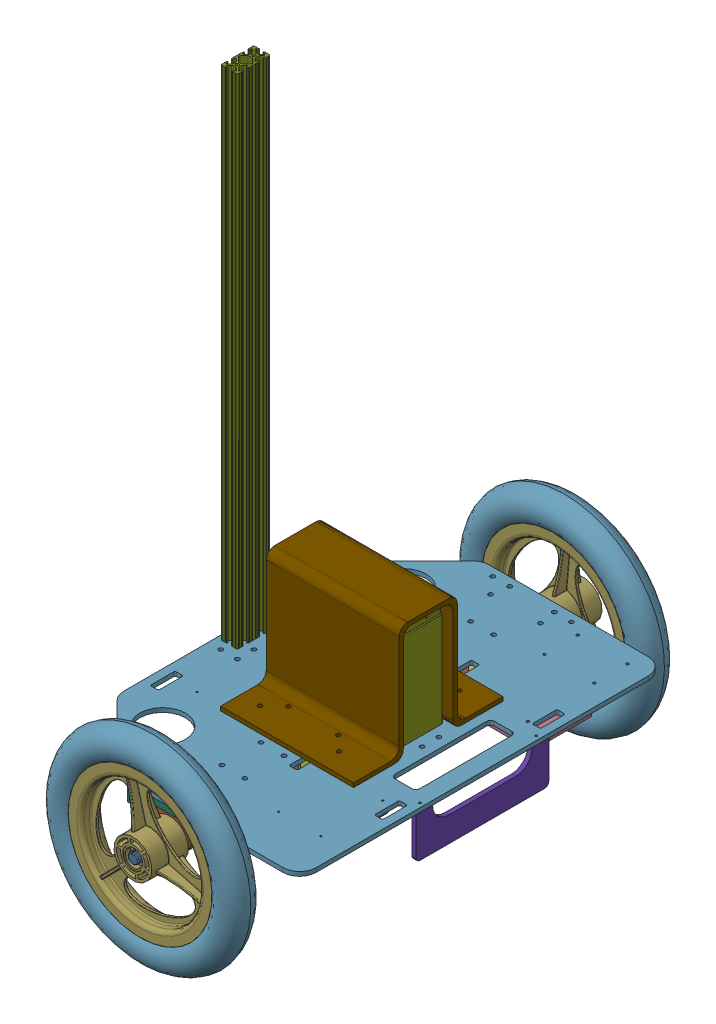
SolidWorks assembly Segway, configuration Default. Lengths in mm.
Overall size (381 985.87 688.87).
122 component instances, 36 part files, 61 mates.
Components (placement in the parent):
- BB2-1: BB2 [Default] at (0.4359 -31.75 -121.9313) x (0 -1 0) z (0 0 1) size (64.41 64.41 215.73)
  - BB2-InterfacePlate-1-1: BB2-InterfacePlate-1 [Default] at origin size (63.5 63.5 3.7)
  - BB2-BackPlate-1-1: BB2-BackPlate-1 [Default] at (0 0 -8.55) x (0 -1 0) z (0 0 1) size (63.5 63.5 22.41)
  - BB2-RingGear-1-1: BB2-RingGear-1 [Default] at (0 0 -15.25) x (1 0 0) z (0 0 -1) size (60 60 46.8)
  - BB2-FrontPlate-1-1: BB2-FrontPlate-1 [Default] at (0 0 -68.4) x (0 1 0) z (0 0 -1) size (63.5 63.5 18.7)
  - br-8-1-1: br-8-1 [Default] at (0 0 -70.7812) x (1 0 0) z (0 0 -1) size (28.57 28.57 7.94)
  - br-8-1-2: br-8-1 [Default] at (0 0 -62.8438) x (0.905117 -0.425162 0) z (0 0 1) size (28.57 28.57 7.94)
  - BB2-OutputShaft-1-1: BB2-OutputShaft-1 [Default] at (0 0 -112.85) x (0.213787 -0.97688 0) z (0 0 1) size (12.7 12.7 59)
  - CIM Motor-1-1: CIM Motor-1 [Default] at (0 0 8.85) x (1 0 0) z (0 0 -1) size (64.41 64.41 149.34)
    - CIM motor-1-1: CIM motor-1 [Default] at origin size (64.41 64.41 149.34)
    - 10-24 UNC x 4_ Phillips Pan Head-1-1: 10-24 UNC x 4_ Phillips Pan Head-1 [Default] at (0 25.4 -98.0336) x (1 0 0) z (0 1 0) size (9.47 105.24 9.47)
    - 10-24 UNC x 4_ Phillips Pan Head-1-2: 10-24 UNC x 4_ Phillips Pan Head-1 [Default] at (0 -25.4 -98.0336) x (-1 0 0) z (0 -1 0) size (9.47 105.24 9.47)
- BB2-2: BB2 [Default] at (0.4359 -31.75 121.9095) x (0 -1 0) z (0 0 -1) size (64.41 64.41 215.73)
  - BB2-InterfacePlate-1-1: BB2-InterfacePlate-1 [Default] at origin size (63.5 63.5 3.7)
  - BB2-BackPlate-1-1: BB2-BackPlate-1 [Default] at (0 0 -8.55) x (0 -1 0) z (0 0 1) size (63.5 63.5 22.41)
  - BB2-RingGear-1-1: BB2-RingGear-1 [Default] at (0 0 -15.25) x (1 0 0) z (0 0 -1) size (60 60 46.8)
  - BB2-FrontPlate-1-1: BB2-FrontPlate-1 [Default] at (0 0 -68.4) x (0 1 0) z (0 0 -1) size (63.5 63.5 18.7)
  - br-8-1-1: br-8-1 [Default] at (0 0 -70.7812) x (1 0 0) z (0 0 -1) size (28.57 28.57 7.94)
  - br-8-1-2: br-8-1 [Default] at (0 0 -62.8438) x (0.905117 -0.425162 0) z (0 0 1) size (28.57 28.57 7.94)
  - BB2-OutputShaft-1-1: BB2-OutputShaft-1 [Default] at (0 0 -112.85) x (0.213787 -0.97688 0) z (0 0 1) size (12.7 12.7 59)
  - CIM Motor-1-1: CIM Motor-1 [Default] at (0 0 8.85) x (1 0 0) z (0 0 -1) size (64.41 64.41 149.34)
    - CIM motor-1-1: CIM motor-1 [Default] at origin size (64.41 64.41 149.34)
    - 10-24 UNC x 4_ Phillips Pan Head-1-1: 10-24 UNC x 4_ Phillips Pan Head-1 [Default] at (0 25.4 -98.0336) x (1 0 0) z (0 1 0) size (9.47 105.24 9.47)
    - 10-24 UNC x 4_ Phillips Pan Head-1-2: 10-24 UNC x 4_ Phillips Pan Head-1 [Default] at (0 -25.4 -98.0336) x (-1 0 0) z (0 -1 0) size (9.47 105.24 9.47)
- coupling-1: coupling [Default] at (0.4359 -31.75 -250.6563) x (0 0 1) z (-0.996462 -0.084047 0) size (50.8 33.34 33.34)
- coupling-2: coupling [Default] at (0.4359 -31.75 250.6345) x (0 0 -1) z (-0.914394 0.404825 0) size (50.8 33.34 33.34)
- 5_8_keyed_shaft-1: 5_8_keyed_shaft [Default] at (0.4359 -31.75 -230.0594) x (0 0 -1) z (-0.98071 -0.195469 0) size (114.47 15.59 15.88)
- 5_8_keyed_shaft-2: 5_8_keyed_shaft [Default] at (0.4359 -31.75 344.3376) x (0 0 -1) z (0.997156 -0.07537 0) size (114.47 15.59 15.88)
- bearing-1: bearing [Default] at (0.4359 -31.75 -279.2313) x (0 0 1) z (1 0 0) size (34.53 44.45 85.72)
- bearing-4: bearing [Default] at (0.4359 -31.75 279.2095) x (0 0 -1) z (-1 0 0) size (34.53 44.45 85.72)
- 12 Inch Wheel-1: 12 Inch Wheel [Default] at (0.4359 -31.75 -316.3594) x (0 0 -1) z (0.995996 -0.0894 0) size (56 304.8 304.8)
  - 12 Inch Wheel Outer Hub-1: 12 Inch Wheel Outer Hub [Default] at origin size (56 220 220)
  - 12 Inch Wheel Inner Hub-1: 12 Inch Wheel Inner Hub [Default] at (18.355 0 0) x (0 0 1) z (-1 0 0) size (27 27 46.36)
  - 12 Inch Tire-1: 12 Inch Tire [Default] at origin size (46.35 304.8 304.8)
- 12 Inch Wheel-2: 12 Inch Wheel [Default] at (0.4359 -31.75 316.3376) x (0 0 1) z (0.250945 0.968001 0) size (56 304.8 304.8)
  - 12 Inch Wheel Outer Hub-1: 12 Inch Wheel Outer Hub [Default] at origin size (56 220 220)
  - 12 Inch Wheel Inner Hub-1: 12 Inch Wheel Inner Hub [Default] at (18.355 0 0) x (0 0 1) z (-1 0 0) size (27 27 46.36)
  - 12 Inch Tire-1: 12 Inch Tire [Default] at origin size (46.35 304.8 304.8)
- bearing spacer-1: bearing spacer [Default] at (-42.4266 -9.525 -253.8313) size (85.72 9.53 25.4)
- bearing spacer-2: bearing spacer [Default] at (-42.4266 -9.525 279.2095) size (85.72 9.53 25.4)
- battery-1: battery [Default] at (-48.3252 6.35 -21.138) x (1 0 0) z (0 1 0) size (177.81 76.21 167.14)
- Maxi Fuse Block-1: Maxi Fuse Block [Default] at (120.15 0 161.55) x (0 0 -1) z (0 -1 0) size (107.5 77.5 38)
  - Maxi Fuse Block - Base-1: Maxi Fuse Block - Base [Default] at origin size (107.5 77.5 19.5)
  - Maxi Fuse Block - Terminal-1: Maxi Fuse Block - Terminal [Default] at (26.42 -26.73 16.2) x (1 0 0) z (0 -1 0) size (28 19.9 11.5)
  - Maxi Fuse Block - Terminal-2: Maxi Fuse Block - Terminal [Default] at (-26.42 -26.73 16.2) x (-1 0 0) z (0 1 0) size (28 19.9 11.5)
  - Maxi Fuse Block - Terminal-3: Maxi Fuse Block - Terminal [Default] at (26.42 -8.91 16.2) x (1 0 0) z (0 -1 0) size (28 19.9 11.5)
  - Maxi Fuse Block - Terminal-4: Maxi Fuse Block - Terminal [Default] at (-26.42 -8.91 16.2) x (-1 0 0) z (0 1 0) size (28 19.9 11.5)
  - Maxi Fuse Block - Terminal-5: Maxi Fuse Block - Terminal [Default] at (26.42 8.91 16.2) x (1 0 0) z (0 -1 0) size (28 19.9 11.5)
  - Maxi Fuse Block - Terminal-6: Maxi Fuse Block - Terminal [Default] at (-26.42 8.91 16.2) x (-1 0 0) z (0 1 0) size (28 19.9 11.5)
  - Maxi Fuse Block - Terminal-7: Maxi Fuse Block - Terminal [Default] at (26.42 26.73 16.2) x (1 0 0) z (0 -1 0) size (28 19.9 11.5)
  - Maxi Fuse Block - Terminal-8: Maxi Fuse Block - Terminal [Default] at (-26.42 26.73 16.2) x (-1 0 0) z (0 1 0) size (28 19.9 11.5)
  - Maxi Fuse Block - Bottom Cover-1: Maxi Fuse Block - Bottom Cover [Default] at (4.987 4.269 1.62) x (-1 0 0) z (0 0 -1) size (84 68 1.62)
  - Maxi Fuse Block - Top Cover-1: Maxi Fuse Block - Top Cover [Default] at (0 0 5.6) size (81 73.4 21.5)
  - Maxi Fuse-1: Maxi Fuse [Default] at (0.245 -26.664 28.75) size (29.25 8.9 31.25)
    - Maxi Fuse - Body-1: Maxi Fuse - Body [Default] at origin size (29.25 8.9 18.5)
    - Maxi Fuse - Terminal-1: Maxi Fuse - Terminal [Default] at (10.625 0 -12.75) x (-1 0 0) z (0 1 0) size (8 18.5 0.86)
    - Maxi Fuse - Terminal-2: Maxi Fuse - Terminal [Default] at (-10.625 0 -12.75) x (1 0 0) z (0 -1 0) size (8 18.5 0.86)
  - Maxi Fuse-2: Maxi Fuse [Default] at (0.245 -8.664 28.75) size (29.25 8.9 31.25)
    - Maxi Fuse - Body-1: Maxi Fuse - Body [Default] at origin size (29.25 8.9 18.5)
    - Maxi Fuse - Terminal-1: Maxi Fuse - Terminal [Default] at (10.625 0 -12.75) x (-1 0 0) z (0 1 0) size (8 18.5 0.86)
    - Maxi Fuse - Terminal-2: Maxi Fuse - Terminal [Default] at (-10.625 0 -12.75) x (1 0 0) z (0 -1 0) size (8 18.5 0.86)
  - Maxi Fuse-3: Maxi Fuse [Default] at (0.245 9.336 28.75) size (29.25 8.9 31.25)
    - Maxi Fuse - Body-1: Maxi Fuse - Body [Default] at origin size (29.25 8.9 18.5)
    - Maxi Fuse - Terminal-1: Maxi Fuse - Terminal [Default] at (10.625 0 -12.75) x (-1 0 0) z (0 1 0) size (8 18.5 0.86)
    - Maxi Fuse - Terminal-2: Maxi Fuse - Terminal [Default] at (-10.625 0 -12.75) x (1 0 0) z (0 -1 0) size (8 18.5 0.86)
  - Maxi Fuse-4: Maxi Fuse [Default] at (0.245 27.336 28.75) size (29.25 8.9 31.25)
    - Maxi Fuse - Body-1: Maxi Fuse - Body [Default] at origin size (29.25 8.9 18.5)
    - Maxi Fuse - Terminal-1: Maxi Fuse - Terminal [Default] at (10.625 0 -12.75) x (-1 0 0) z (0 1 0) size (8 18.5 0.86)
    - Maxi Fuse - Terminal-2: Maxi Fuse - Terminal [Default] at (-10.625 0 -12.75) x (1 0 0) z (0 -1 0) size (8 18.5 0.86)
- Victor884-1: Victor884 [Default] at (-101.5293 0.127 63.0431) x (0 0 -1) z (0 -1 0) size (69.65 56.95 53.28)
  - Victor884-Cover-1: Victor884-Cover [Default] at origin size (69.65 56.95 53.28)
  - Fan-PAPST-412-1: Fan-PAPST-412 [Default] at (-18.7322 -1.3534 40.2082) x (1 0 0) z (0 0 -1) size (39.88 39.88 20.07)
  - Victor884-Base-1: Victor884-Base [Default] at (6.7866 -24.0693 0.127) size (66.29 53.59 9.91)
  - Victor884-Capacitor-1: Victor884-Capacitor [Default] at (-18.6052 -1.2264 18.3642) x (0.989031 0.147708 0) z (0 0 1) size (12.7 12.7 20.33)
  - Victor884-LED - Green-1: Victor884-LED - Green [Default] at (7.0869 -27.9091 8.7012) x (0.893703 -0.448659 0) z (-0.448659 -0.893703 0) size (5.9 9 5.9)
  - Victor884-Fet-1: Victor884-Fet [Default] at (-12.6489 -15.1964 10.8712) x (0 1 0) z (1 0 0) size (10.16 22.61 4.47)
  - Victor884-Fet-2: Victor884-Fet [Default] at (-20.0149 -15.1964 10.8712) x (0 1 0) z (1 0 0) size (10.16 22.61 4.47)
  - Victor884-Fet-3: Victor884-Fet [Default] at (-27.3809 -15.1964 10.8712) x (0 1 0) z (1 0 0) size (10.16 22.61 4.47)
  - Victor884-Fet-4: Victor884-Fet [Default] at (-4.6352 4.7299 10.8712) x (-1 0 0) z (0 1 0) size (10.16 22.61 4.47)
  - Victor884-Fet-5: Victor884-Fet [Default] at (-4.6352 -2.6361 10.8712) x (-1 0 0) z (0 1 0) size (10.16 22.61 4.47)
  - Victor884-Fet-6: Victor884-Fet [Default] at (-4.6352 -10.0021 10.8712) x (-1 0 0) z (0 1 0) size (10.16 22.61 4.47)
  - Victor884-Fet-7: Victor884-Fet [Default] at (-24.5615 12.7436 10.8712) x (0 -1 0) z (-1 0 0) size (10.16 22.61 4.47)
  - Victor884-Fet-8: Victor884-Fet [Default] at (-17.1955 12.7436 10.8712) x (0 -1 0) z (-1 0 0) size (10.16 22.61 4.47)
  - Victor884-Fet-9: Victor884-Fet [Default] at (-9.8295 12.7436 10.8712) x (0 -1 0) z (-1 0 0) size (10.16 22.61 4.47)
  - Victor884-Fet-10: Victor884-Fet [Default] at (-32.5752 -7.1827 10.8712) x (1 0 0) z (0 -1 0) size (10.16 22.61 4.47)
  - Victor884-Fet-11: Victor884-Fet [Default] at (-32.5752 0.1833 10.8712) x (1 0 0) z (0 -1 0) size (10.16 22.61 4.47)
  - Victor884-Fet-12: Victor884-Fet [Default] at (-32.5752 7.5493 10.8712) x (1 0 0) z (0 -1 0) size (10.16 22.61 4.47)
  - Victor884 Screw Terminal-1: Victor884 Screw Terminal [Default] at (-48.5772 12.6166 13.9192) x (1 0 0) z (0 0 -1) size (7.87 7.87 10.34)
  - Victor884 Screw Terminal-2: Victor884 Screw Terminal [Default] at (-48.5772 2.4566 13.9192) x (1 0 0) z (0 0 -1) size (7.87 7.87 10.34)
  - Victor884 Screw Terminal-3: Victor884 Screw Terminal [Default] at (3.6198 12.6166 13.9192) x (1 0 0) z (0 0 -1) size (7.87 7.87 10.34)
  - Victor884 Screw Terminal-4: Victor884 Screw Terminal [Default] at (3.6198 2.4566 13.9192) x (1 0 0) z (0 0 -1) size (7.87 7.87 10.34)
  - Victor884-3 Pin Connector-1: Victor884-3 Pin Connector [Default] at (-48.3232 -24.0229 8.3312) x (0 -1 0) z (0 0 1) size (2.54 7.62 11.43)
- Victor884-2: Victor884 [Default] at (-116.1487 0.127 -63.0431) x (0 0 1) z (0 -1 0) size (69.65 56.95 53.28)
  - Victor884-Cover-1: Victor884-Cover [Default] at origin size (69.65 56.95 53.28)
  - Fan-PAPST-412-1: Fan-PAPST-412 [Default] at (-18.7322 -1.3534 40.2082) x (1 0 0) z (0 0 -1) size (39.88 39.88 20.07)
  - Victor884-Base-1: Victor884-Base [Default] at (6.7866 -24.0693 0.127) size (66.29 53.59 9.91)
  - Victor884-Capacitor-1: Victor884-Capacitor [Default] at (-18.6052 -1.2264 18.3642) x (0.989031 0.147708 0) z (0 0 1) size (12.7 12.7 20.33)
  - Victor884-LED - Green-1: Victor884-LED - Green [Default] at (7.0869 -27.9091 8.7012) x (0.893703 -0.448659 0) z (-0.448659 -0.893703 0) size (5.9 9 5.9)
  - Victor884-Fet-1: Victor884-Fet [Default] at (-12.6489 -15.1964 10.8712) x (0 1 0) z (1 0 0) size (10.16 22.61 4.47)
  - Victor884-Fet-2: Victor884-Fet [Default] at (-20.0149 -15.1964 10.8712) x (0 1 0) z (1 0 0) size (10.16 22.61 4.47)
  - Victor884-Fet-3: Victor884-Fet [Default] at (-27.3809 -15.1964 10.8712) x (0 1 0) z (1 0 0) size (10.16 22.61 4.47)
  - Victor884-Fet-4: Victor884-Fet [Default] at (-4.6352 4.7299 10.8712) x (-1 0 0) z (0 1 0) size (10.16 22.61 4.47)
  - Victor884-Fet-5: Victor884-Fet [Default] at (-4.6352 -2.6361 10.8712) x (-1 0 0) z (0 1 0) size (10.16 22.61 4.47)
  - Victor884-Fet-6: Victor884-Fet [Default] at (-4.6352 -10.0021 10.8712) x (-1 0 0) z (0 1 0) size (10.16 22.61 4.47)
  - Victor884-Fet-7: Victor884-Fet [Default] at (-24.5615 12.7436 10.8712) x (0 -1 0) z (-1 0 0) size (10.16 22.61 4.47)
  - Victor884-Fet-8: Victor884-Fet [Default] at (-17.1955 12.7436 10.8712) x (0 -1 0) z (-1 0 0) size (10.16 22.61 4.47)
  - Victor884-Fet-9: Victor884-Fet [Default] at (-9.8295 12.7436 10.8712) x (0 -1 0) z (-1 0 0) size (10.16 22.61 4.47)
  - Victor884-Fet-10: Victor884-Fet [Default] at (-32.5752 -7.1827 10.8712) x (1 0 0) z (0 -1 0) size (10.16 22.61 4.47)
  - Victor884-Fet-11: Victor884-Fet [Default] at (-32.5752 0.1833 10.8712) x (1 0 0) z (0 -1 0) size (10.16 22.61 4.47)
  - Victor884-Fet-12: Victor884-Fet [Default] at (-32.5752 7.5493 10.8712) x (1 0 0) z (0 -1 0) size (10.16 22.61 4.47)
  - Victor884 Screw Terminal-1: Victor884 Screw Terminal [Default] at (-48.5772 12.6166 13.9192) x (1 0 0) z (0 0 -1) size (7.87 7.87 10.34)
  - Victor884 Screw Terminal-2: Victor884 Screw Terminal [Default] at (-48.5772 2.4566 13.9192) x (1 0 0) z (0 0 -1) size (7.87 7.87 10.34)
  - Victor884 Screw Terminal-3: Victor884 Screw Terminal [Default] at (3.6198 12.6166 13.9192) x (1 0 0) z (0 0 -1) size (7.87 7.87 10.34)
  - Victor884 Screw Terminal-4: Victor884 Screw Terminal [Default] at (3.6198 2.4566 13.9192) x (1 0 0) z (0 0 -1) size (7.87 7.87 10.34)
  - Victor884-3 Pin Connector-1: Victor884-3 Pin Connector [Default] at (-48.3232 -24.0229 8.3312) x (0 -1 0) z (0 0 1) size (2.54 7.62 11.43)
- controller-1: controller [Default] at (76.2 -7.9502 -260.35) x (0 0 1) z (-1 0 0) size (165.1 28.6 88.9)
- base-1: base [Default] x (0 0 -1) z (1 0 0) size (558.8 6.35 381)
- beam-1: beam [Default] at (-47.1891 0 -279.4) x (0 0 1) z (1 0 0) size (558.8 25.4 25.4)
- beam-2: beam [Default] at (73.4609 0 -279.4) x (0 0 1) z (1 0 0) size (558.8 25.4 25.4)
- 8020-1020-36in-1: 8020-1020-36in [Default] at (-87.6335 6.35 -41.3302) x (0 0 1) z (0 -1 0) size (50.8 25.4 762)
- plate-1: plate [Default] at (190.5 0 -0.117) x (0 0 1) z (-1 0 0) size (203.2 63.5 6.35)
- batteryholder-1: batteryholder [Default] at (113.0313 6.35 -109.1178) x (0 0 1) z (-1 0 0) size (228.6 177.8 203.2)
Mates (geometry in assembly coordinates):
- Concentric1: concentric anti-aligned: cylinder of BB2-1/BB2-OutputShaft-1-1; cylinder of BB2-2/BB2-OutputShaft-1-1
- Coincident1: coincident aligned: plane of BB2-1/BB2-BackPlate-1-1 through (35.3609 0 -123.1113) normal (0 1 0); plane of BB2-2/BB2-BackPlate-1-1 through (-34.4891 0 123.0895) normal (0 1 0)
- Distance1: distance = 12.7 mm anti-aligned: plane of BB2-1/CIM Motor-1-1/CIM motor-1-1 through (16.1801 -47.4942 -6.3609) normal (0 0 1); plane of BB2-2/CIM Motor-1-1/CIM motor-1-1 through (-15.3083 -47.4942 6.3391) normal (0 0 -1)
- Concentric2: concentric aligned: cylinder of BB2-1/BB2-OutputShaft-1-1; cylinder of coupling-1
- Concentric3: concentric aligned: cylinder of BB2-2/BB2-OutputShaft-1-1; cylinder of coupling-2
- Distance2: distance = 3.175 mm anti-aligned: plane of BB2-2/BB2-FrontPlate-1-1 through (35.3609 3.175 196.6595) normal (0 0 1); plane of coupling-2 through (0.4359 -31.75 199.8345) normal (0 0 -1)
- Distance3: distance = 3.175 mm anti-aligned: plane of BB2-1/BB2-FrontPlate-1-1 through (-34.4891 3.175 -196.6813) normal (0 0 -1); plane of coupling-1 through (0.4359 -31.75 -199.8563) normal (0 0 1)
- Concentric4: concentric anti-aligned: cylinder of coupling-1; cylinder of 5_8_keyed_shaft-1
- Concentric5: concentric aligned: cylinder of coupling-2; cylinder of 5_8_keyed_shaft-2
- Concentric6: concentric aligned: cylinder of 5_8_keyed_shaft-1; cylinder of bearing-1
- Parallel1: parallel aligned: plane of BB2-1/BB2-FrontPlate-1-1 through (-34.4891 0 -197.3163) normal (0 1 0); plane of bearing-1 through (-80.0705 -9.525 -253.8313) normal (0 1 0)
- Concentric8: concentric anti-aligned: cylinder of 5_8_keyed_shaft-2; cylinder of bearing-4
- Parallel2: parallel aligned: plane of BB2-2/BB2-FrontPlate-1-1 through (35.3609 0 197.2945) normal (0 1 0); plane of bearing-4 through (80.9423 -9.525 253.8095) normal (0 1 0)
- Distance7: distance = 3.175 mm anti-aligned: plane of coupling-1 through (0.4359 -31.75 -250.6563) normal (0 0 -1); plane of bearing-1 through (-80.0705 -16.0521 -253.8313) normal (0 0 1)
- Distance8: distance = 3.175 mm anti-aligned: plane of coupling-2 through (0.4359 -31.75 250.6345) normal (0 0 1); plane of bearing-4 through (80.9423 -16.0521 253.8095) normal (0 0 -1)
- Concentric13: concentric aligned: cylinder of 5_8_keyed_shaft-1; cylinder of 12 Inch Wheel-1/12 Inch Wheel Inner Hub-1
- Concentric14: concentric anti-aligned: cylinder of 5_8_keyed_shaft-2; cylinder of 12 Inch Wheel-2/12 Inch Wheel Inner Hub-1
- Coincident22: coincident anti-aligned: plane of bearing-4 through (0.4359 -31.75 288.3376) normal (0 0 1); plane of 12 Inch Wheel-2/12 Inch Wheel Inner Hub-1 through (-17.6655 -42.3983 288.3376) normal (0 0 -1)
- Coincident23: coincident anti-aligned: plane of bearing-1 through (0.4359 -31.75 -288.3594) normal (0 0 -1); plane of 12 Inch Wheel-1/12 Inch Wheel Inner Hub-1 through (-15.6822 -45.213 -288.3594) normal (0 0 1)
- Coincident14: coincident anti-aligned: plane of bearing-4 through (80.9423 -9.525 253.8095) normal (0 1 0); plane of bearing spacer-2 through (-42.4266 -9.525 253.8095) normal (0 -1 0)
- Concentric15: concentric anti-aligned: cylinder of bearing-4; cylinder of bearing spacer-2
- Coincident15: coincident aligned: plane of bearing-4 through (43.2984 -16.0521 253.8095) normal (1 0 0); plane of bearing spacer-2 through (43.2984 0 279.2095) normal (1 0 0)
- Concentric16: concentric anti-aligned: cylinder of bearing-1; cylinder of bearing spacer-1
- Coincident16: coincident anti-aligned: plane of bearing-1 through (-80.0705 -9.525 -253.8313) normal (0 1 0); plane of bearing spacer-1 through (-42.4266 -9.525 -279.2313) normal (0 -1 0)
- Coincident17: coincident: line of bearing-1; plane of bearing spacer-1 through (43.2984 0 -253.8313) normal (1 0 0)
- Coincident19: coincident anti-aligned: plane of BB2-2/BB2-FrontPlate-1-1 through (35.3609 0 197.2945) normal (0 1 0); plane of base-1 through (-190.5 0 279.4) normal (0 -1 0)
- Parallel3: parallel aligned: plane of BB2-1/BB2-BackPlate-1-1 through (32.1859 3.175 -137.8513) normal (1 0 0); plane of base-1 through (190.5 6.35 279.4) normal (1 0 0)
- Concentric21: concentric anti-aligned: cylinder of BB2-2/BB2-FrontPlate-1-1; cylinder of base-1
- Coincident29: coincident aligned: plane of beam-1 through (-47.1891 -25.4 -279.4) normal (0 0 -1); plane of base-1 through (190.5 6.35 -279.4) normal (0 0 -1)
- Coincident31: coincident aligned: plane of base-1 through (190.5 6.35 -279.4) normal (0 0 -1); plane of beam-2 through (73.4609 -25.4 -279.4) normal (0 0 -1)
- Coincident39: coincident anti-aligned: plane of battery-1 through (105.2518 6.35 44.8852) normal (0 -1 0); plane of base-1 through (-190.5 6.35 279.4) normal (0 1 0)
- Parallel7: parallel: plane of battery-1 through (96.3618 158.369 42.0912) normal (1 0 0); line of base-1
- Distance11: distance = 6.35 mm anti-aligned: plane of controller-1 through (165.1 -6.35 -260.35) normal (0 1 0); plane of base-1 through (-190.5 0 279.4) normal (0 -1 0)
- Parallel8: parallel aligned: plane of controller-1 through (165.1 -6.35 -260.35) normal (1 0 0); plane of base-1 through (190.5 6.35 279.4) normal (1 0 0)
- Coincident46: coincident anti-aligned: plane of Victor884-2/Victor884-Base-1 through (-76.56 0 -45.3219) normal (0 1 0); plane of base-1 through (-190.5 0 279.4) normal (0 -1 0)
- Coincident47: coincident anti-aligned: plane of Victor884-1/Victor884-Base-1 through (-141.118 0 45.3219) normal (0 1 0); plane of base-1 through (-190.5 0 279.4) normal (0 -1 0)
- Coincident48: coincident anti-aligned: plane of Maxi Fuse Block-1/Maxi Fuse Block - Base-1 through (77.525 0 102.425) normal (0 1 0); plane of base-1 through (-190.5 0 279.4) normal (0 -1 0)
- Coincident49: coincident: point of base-1; point of assembly
- Coincident50: coincident anti-aligned: plane of base-1 through (-190.5 0 279.4) normal (0 -1 0); plane of assembly
- Coincident51: coincident aligned: plane of base-1 through (0 0 0) normal (1 0 0); plane of assembly
- Coincident52: coincident anti-aligned: plane of 5_8_keyed_shaft-1 through (0.4359 -31.75 -344.3594) normal (0 0 -1); circle of ? centre (0.4359 -31.75 -344.3594) axis (0 0 1)
- Coincident53: coincident anti-aligned: plane of 5_8_keyed_shaft-2 through (0.4359 -31.75 344.3376) normal (0 0 1); circle of ? centre (0.4359 -31.75 344.3376) axis (0 0 -1)
- Coincident58: coincident anti-aligned: plane of base-1 through (-190.5 0 279.4) normal (0 -1 0); plane of beam-1 through (-47.1891 0 279.4) normal (0 1 0)
- Distance17: distance = 4.7625 mm anti-aligned: plane of bearing spacer-1 through (-42.4266 0 -253.8313) normal (-1 0 0); plane of beam-1 through (-47.1891 0 279.4) normal (1 0 0)
- Coincident60: coincident anti-aligned: plane of base-1 through (-190.5 0 279.4) normal (0 -1 0); plane of beam-2 through (73.4609 0 279.4) normal (0 1 0)
- Distance18: distance = 4.7625 mm anti-aligned: plane of bearing spacer-1 through (43.2984 0 -253.8313) normal (1 0 0); plane of beam-2 through (48.0609 0 279.4) normal (-1 0 0)
- Parallel9: parallel aligned: plane of Maxi Fuse Block-1/Maxi Fuse Block - Base-1 through (81.4 -7.98 213.525) normal (-1 0 0); plane of base-1 through (-190.5 6.35 279.4) normal (-1 0 0)
- Concentric22: concentric aligned: cylinder of controller-1; cylinder of base-1
- Concentric23: concentric anti-aligned: cylinder of Maxi Fuse Block-1/Maxi Fuse Block - Base-1; cylinder of base-1
- Concentric24: concentric anti-aligned: cone of Victor884-1/Victor884-Cover-1; cylinder of base-1
- Parallel10: parallel: plane of Victor884-1/Victor884-Cover-1 through (-136.3865 -11.1141 113.6315) normal (-0.999391 -0.034899 0); line of base-1
- Parallel11: parallel: line of Victor884-2/Victor884-Cover-1; plane of base-1 through (-190.5 6.35 279.4) normal (-1 0 0)
- Concentric25: concentric anti-aligned: cone of Victor884-2/Victor884-Cover-1; cylinder of base-1
- Coincident62: coincident anti-aligned: plane of base-1 through (-190.5 6.35 279.4) normal (0 1 0); plane of 8020-1020-36in-1 through (-156.21 6.35 -30.4799) normal (0 -1 0)
- Parallel12: parallel aligned: plane of base-1 through (-190.5 6.35 279.4) normal (-1 0 0); plane of 8020-1020-36in-1 through (-184.1497 34.29 -2.5579) normal (-1 0 0)
- Concentric27: concentric anti-aligned: cylinder of base-1; cylinder of 8020-1020-36in-1
- Coincident63: coincident aligned: plane of base-1 through (190.5 6.35 279.4) normal (1 0 0); plane of plate-1 through (190.5 0 50.683) normal (1 0 0)
- Coincident64: coincident anti-aligned: plane of base-1 through (-190.5 0 279.4) normal (0 -1 0); plane of plate-1 through (184.15 0 76.083) normal (0 1 0)
- Coincident65: coincident: plane of base-1 through (-190.5 6.35 279.4) normal (0 1 0); plane of batteryholder-1 through (-89.2795 6.35 -109.7904) normal (0 -1 0)
- Concentric28: concentric: cylinder of base-1; cylinder of batteryholder-1
- Parallel13: parallel aligned: plane of base-1; plane of batteryholder-1
